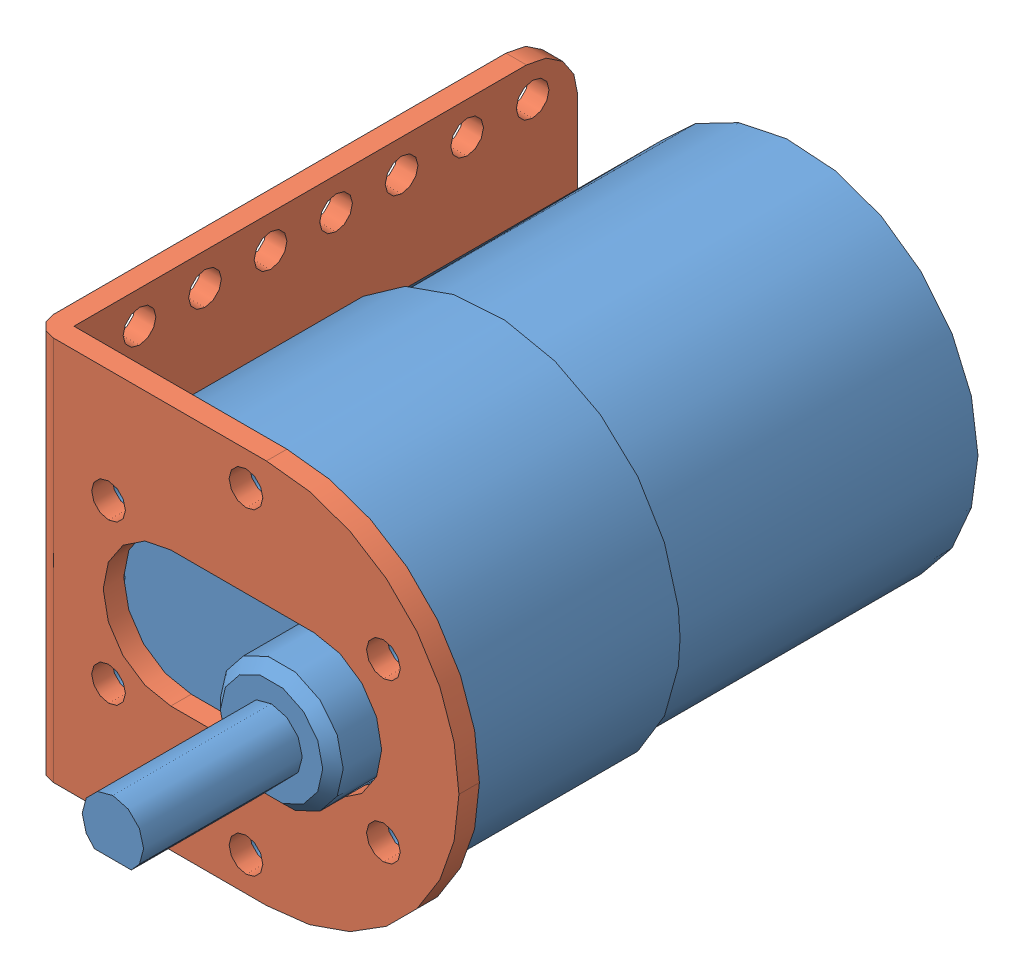
SolidWorks assembly Assem2, configuration Default. Lengths in mm.
Overall size (41.6 37.6 74).
2 component instances, 2 part files, 3 mates.
Components (placement in the parent):
- 37D_30_1 motor-1: 37D_30_1 motor [Default] at (26.5335 41.1786 55.6358) size (36.8 36.8 74)
- bracket-1: bracket [Default] at (5.7335 41.1786 54.0358) x (0 0 -1) z (0 -1 0) size (51.2 41.6 37.6)
Mates (geometry in assembly coordinates):
- Coincident1: coincident: plane of 37D_30_1 motor-1 through (26.5335 41.1786 77.6358) normal (0 0 1); plane of bracket-1 through (-21.1133 37.8786 77.6358) normal (0 0 -1)
- Concentric3: concentric: cylinder of 37D_30_1 motor-1 through (13.1101 48.9286 65.6358) axis (0 0 1) radius 1.7; cylinder of bracket-1 through (13.1101 48.9286 28.4348) axis (0 0 1) radius 1.65
- Concentric4: concentric aligned: cylinder of 37D_30_1 motor-1 through (13.1101 33.4286 65.6358) axis (0 0 1) radius 1.7; cylinder of bracket-1 through (13.1101 33.4286 28.4348) axis (0 0 1) radius 1.65
